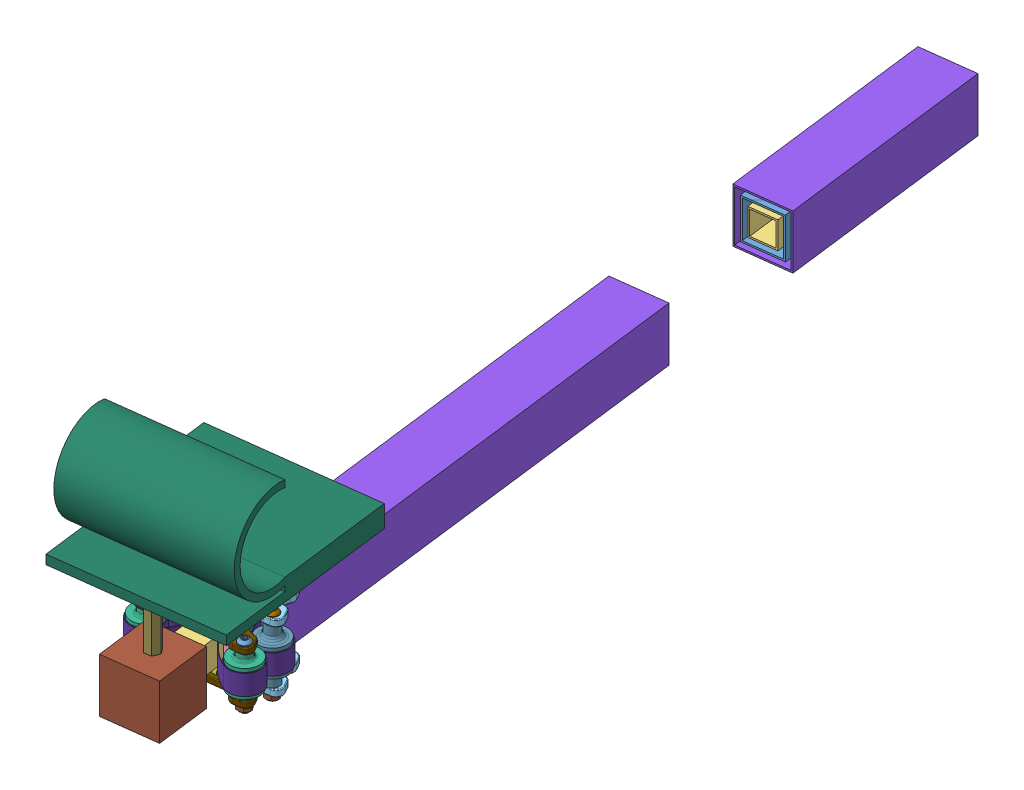
SolidWorks assembly climber prototype2, configuration Default. Lengths in mm.
Overall size (269.94 274.38 951.32).
100 component instances, 33 part files, 13 mates.
Components (placement in the parent):
- 2 x 2 Inch Stage.stp-1: 2 x 2 Inch Stage.stp [Default] at (1113.4745 353.0023 985.2524) size (183.93 74.15 806.3)
  - 1.5_inch_stage.stp-1: 1.5_inch_stage.stp [Default] at (-107.3783 0 -858.4701) size (133.34 47.37 731.79)
    - 1.5x1.5 bar.stp-1: 1.5x1.5 bar.stp [Default] at (575.8182 404.7167 1377.5179) x (-0.992268 0 0.124114) z (-0.124114 0 -0.992268) size (38.1 38.1 711.2)
    - 2x2StageInternalEndBlock.stp-1: 2x2StageInternalEndBlock.stp [Default] at (413.7616 573.8056 681.0462) x (-0.992268 0 0.124114) z (-0.124114 0 -0.992268) size (47.37 47.37 40.64)
    - 94615A115_Brass Flanged Screw-to-Expand Inserts (1).stp-1: 94615A115_Brass Flanged Screw-to-Expand Inserts (1).stp [Default] at (431.7042 573.8056 688.4011) x (0.114575 0.384452 0.916007) z (-0.047716 0.923145 -0.381479) size (7.92 9.53 7.92)
    - 97763A231_18-8 Stainless Steel Button Head Hex Drive Screws.stp-1: 97763A231_18-8 Stainless Steel Button Head Hex Drive Screws.stp [Default] at (398.9269 573.8691 692.501) x (0.124114 0.000773 0.992268) z (-0.992268 0 0.124114) size (9.17 9.17 12.09)
  - 2x2ClimberPlateAssemblyNew.stp-1: 2x2ClimberPlateAssemblyNew.stp [Default] at (310.1471 56.4224 225.65) x (0.992268 0 -0.124114) z (0.124114 0 0.992268) size (102.18 13.04 44.45)
    - 2x2NewClimberPlateConcept.stp-1: 2x2NewClimberPlateConcept.stp [Default] at (71.6924 542.7705 -285.0056) x (-1 0 0) z (0 1 0) size (102.18 44.45 8.76)
    - 98381A545_ALLOY STEEL DOWEL PIN.stp-1: 98381A545_ALLOY STEEL DOWEL PIN.stp [Default] at (46.4194 542.6435 281.8589) x (-1 0 0) z (0 -0.467381 0.884056) size (34.92 6.35 6.35)
    - TTB-0027_.50OD_.25ID_.188WD.stp-1: TTB-0027_.50OD_.25ID_.188WD.stp [Default] at (31.3382 542.6435 281.8589) x (0 0.013886 0.999904) z (-1 0 0) size (12.7 12.7 4.76)
    - TTB-0027_.50OD_.25ID_.188WD.stp-2: TTB-0027_.50OD_.25ID_.188WD.stp [Default] at (61.5007 542.6435 281.8589) x (0 0.005291 0.999986) z (-1 0 0) size (12.7 12.7 4.76)
  - 2x2ClimberPlateAssemblyNew.stp-2: 2x2ClimberPlateAssemblyNew.stp [Default] at (402.0161 1091.1635 214.1589) x (-0.992268 0 0.124114) z (0.124114 0 0.992268) size (102.18 13.04 44.45)
    - 2x2NewClimberPlateConcept.stp-1: 2x2NewClimberPlateConcept.stp [Default] at (71.6924 542.7705 -285.0056) x (-1 0 0) z (0 1 0) size (102.18 44.45 8.76)
    - 98381A545_ALLOY STEEL DOWEL PIN.stp-1: 98381A545_ALLOY STEEL DOWEL PIN.stp [Default] at (46.4194 542.6435 281.8589) x (-1 0 0) z (0 -0.467381 0.884056) size (34.92 6.35 6.35)
    - TTB-0027_.50OD_.25ID_.188WD.stp-1: TTB-0027_.50OD_.25ID_.188WD.stp [Default] at (31.3382 542.6435 281.8589) x (0 0.013886 0.999904) z (-1 0 0) size (12.7 12.7 4.76)
    - TTB-0027_.50OD_.25ID_.188WD.stp-2: TTB-0027_.50OD_.25ID_.188WD.stp [Default] at (61.5007 542.6435 281.8589) x (0 0.005291 0.999986) z (-1 0 0) size (12.7 12.7 4.76)
  - 2x2 Box.stp-1: 2x2 Box.stp [Default] at (320.6921 548.3929 -267.6788) x (-0.992268 0 0.124114) z (0.124114 0 0.992268) size (50.8 50.8 762)
  - 91255A529_NO THREADS_Button Head Hex Drive Screw (1).stp-1: 91255A529_NO THREADS_Button Head Hex Drive Screw (1).stp [Default] at (366.1553 609.0227 504.1716) x (0.396837 0 -0.917889) z (0 1 0) size (11.1 11.1 73.2)
  - 90044A515_Black-Oxide Alloy Steel Socket Head Screw.stp-1: 90044A515_Black-Oxide Alloy Steel Socket Head Screw.stp [Default] at (410.673 605.6699 482.6046) x (0.993633 0 -0.112668) z (0 1 0) size (6.86 6.86 74.15)
  - 90044A515_Black-Oxide Alloy Steel Socket Head Screw.stp-2: 90044A515_Black-Oxide Alloy Steel Socket Head Screw.stp [Default] at (367.8773 605.6699 487.9575) x (0.430705 0 0.902493) z (0 1 0) size (6.86 6.86 74.15)
  - 91255A529_NO THREADS_Button Head Hex Drive Screw (1).stp-2: 91255A529_NO THREADS_Button Head Hex Drive Screw (1).stp [Default] at (351.7432 609.0227 521.973) x (-0.099638 0 0.995024) z (0 1 0) size (11.1 11.1 73.2)
  - 91255A529_NO THREADS_Button Head Hex Drive Screw (1).stp-3: 91255A529_NO THREADS_Button Head Hex Drive Screw (1).stp [Default] at (434.6883 609.0227 511.5981) x (1 0 0) z (0 1 0) size (11.1 11.1 73.2)
  - 91255A529_NO THREADS_Button Head Hex Drive Screw (1).stp-4: 91255A529_NO THREADS_Button Head Hex Drive Screw (1).stp [Default] at (416.3356 609.0227 497.895) x (0.998718 0 -0.050617) z (0 1 0) size (11.1 11.1 73.2)
  - TTB-0027_.50OD_.25ID_.188WD.stp-1: TTB-0027_.50OD_.25ID_.188WD.stp [Default] at (416.3356 557.2004 497.895) x (-0.032207 0 0.999481) z (0 1 0) size (12.7 12.7 4.76)
  - TTB-0027_.50OD_.25ID_.188WD.stp-2: TTB-0027_.50OD_.25ID_.188WD.stp [Default] at (416.3356 590.4617 497.895) x (-0.065423 0 0.997858) z (0 1 0) size (12.7 12.7 4.76)
  - TTB-0027_.50OD_.25ID_.188WD.stp-3: TTB-0027_.50OD_.25ID_.188WD.stp [Default] at (366.1553 557.2004 504.1716) x (-0.065423 0 0.997858) z (0 1 0) size (12.7 12.7 4.76)
  - TTB-0027_.50OD_.25ID_.188WD.stp-4: TTB-0027_.50OD_.25ID_.188WD.stp [Default] at (366.1553 590.4617 504.1716) x (-0.065423 0 0.997858) z (0 1 0) size (12.7 12.7 4.76)
  - 90101A230_18-8 Stainless Steel Thin Nylon-Insert Locknut.stp-1: 90101A230_18-8 Stainless Steel Thin Nylon-Insert Locknut.stp [Default] at (434.6883 541.9159 511.5981) x (0.797272 0 -0.60362) z (-0.60362 0 -0.797272) size (11.11 5.2 12.83)
  - 90101A230_18-8 Stainless Steel Thin Nylon-Insert Locknut.stp-2: 90101A230_18-8 Stainless Steel Thin Nylon-Insert Locknut.stp [Default] at (416.3356 541.9159 497.895) x (0.921386 0 0.388648) z (0.388648 0 -0.921386) size (11.11 5.2 12.83)
  - 90101A230_18-8 Stainless Steel Thin Nylon-Insert Locknut.stp-3: 90101A230_18-8 Stainless Steel Thin Nylon-Insert Locknut.stp [Default] at (351.7432 541.9159 521.973) x (0.797272 0 -0.60362) z (-0.60362 0 -0.797272) size (11.11 5.2 12.83)
  - 90101A230_18-8 Stainless Steel Thin Nylon-Insert Locknut.stp-4: 90101A230_18-8 Stainless Steel Thin Nylon-Insert Locknut.stp [Default] at (366.1553 541.9159 504.1716) x (0.797272 0 -0.60362) z (-0.60362 0 -0.797272) size (11.11 5.2 12.83)
  - QuaterInchTelescopingSpacer.stp-1: QuaterInchTelescopingSpacer.stp [Default] at (391.2422 599.1929 504.1716) x (1 0 0) z (0 -1 0) size (9.27 9.27 6.35)
  - QuaterInchTelescopingSpacer.stp-2: QuaterInchTelescopingSpacer.stp [Default] at (391.2422 554.8191 504.1844) x (1 0 0.000511) z (0 -1 0) size (9.27 9.27 6.35)
  - 1.122InchTelescopingSpacer.stp-1: 1.122InchTelescopingSpacer.stp [Default] at (391.2422 588.0804 504.1716) x (1 0 0) z (0 -1 0) size (8.76 8.76 28.5)
  - QuaterInchTelescopingSpacer.stp-3: QuaterInchTelescopingSpacer.stp [Default] at (440.4399 599.1929 504.8475) x (0.96083 0 0.277139) z (0 -1 0) size (9.27 9.27 6.35)
  - QuaterInchTelescopingSpacer.stp-4: QuaterInchTelescopingSpacer.stp [Default] at (409.5553 554.8191 522.0482) x (-0.270275 0 0.962783) z (0 -1 0) size (9.27 9.27 6.35)
  - 94615A115_Brass Flanged Screw-to-Expand Inserts (1).stp-1: 94615A115_Brass Flanged Screw-to-Expand Inserts (1).stp [Default] at (290.8052 573.8056 -165.8762) x (0.123955 0.050546 0.991) z (0.006274 -0.998722 0.050156) size (7.92 9.53 7.92)
  - 97763A231_18-8 Stainless Steel Button Head Hex Drive Screws.stp-1: 97763A231_18-8 Stainless Steel Button Head Hex Drive Screws.stp [Default] at (323.7085 573.8691 -169.9917) x (-0.124114 0 -0.992268) z (0.992268 0 -0.124114) size (9.17 9.17 12.09)
  - 1.122InchTelescopingSpacer.stp-2: 1.122InchTelescopingSpacer.stp [Default] at (441.4226 588.0804 497.895) x (1 0 0) z (0 -1 0) size (8.76 8.76 28.5)
  - 1InchCFSpringRetentionSpacer_BaseStage.stp-1: 1InchCFSpringRetentionSpacer_BaseStage.stp [Default] at (351.7432 564.2679 521.973) x (1 0 0) z (0 -1 0) size (27.94 27.94 15.88)
  - 1InchCFSpringRetentionSpacer_BaseStage.stp-2: 1InchCFSpringRetentionSpacer_BaseStage.stp [Default] at (434.6883 583.3179 511.5981) x (-0.043542 0 0.999052) z (0 1 0) size (27.94 27.94 15.88)
  - 1InchCFSpringRetentionSpacer_BaseStage.stp-3: 1InchCFSpringRetentionSpacer_BaseStage.stp [Default] at (351.7432 583.3179 521.973) x (1 0 0) z (0 1 0) size (27.94 27.94 15.88)
  - 1InchCFSpringRetentionSpacer_BaseStage.stp-4: 1InchCFSpringRetentionSpacer_BaseStage.stp [Default] at (434.6883 564.2679 511.5981) x (0.999991 0 -0.00417) z (0 -1 0) size (27.94 27.94 15.88)
  - 90101A009_18-8 Stainless Steel Thin Nylon-Insert Locknut (1).stp-1: 90101A009_18-8 Stainless Steel Thin Nylon-Insert Locknut (1).stp [Default] at (368.252 541.9159 487.9106) x (0.797272 0 -0.60362) z (-0.60362 0 -0.797272) size (8.73 4.37 10.08)
  - 9293K56_SpringRoller.stp-1: 9293K56_SpringRoller.stp [Default] at (351.7432 564.2679 521.973) x (0.41705 0 -0.908884) z (0 1 0) size (20.07 20.07 19.05)
  - 9293K56_SpringRoller.stp-2: 9293K56_SpringRoller.stp [Default] at (434.6883 583.3179 511.5981) x (0.41705 0 0.908884) z (0 -1 0) size (20.07 20.07 19.05)
  - 9293K56_Constant-Force Spring.stp-1: 9293K56_Constant-Force Spring.stp [Default] at (434.7326 573.7929 511.5599) x (0 -1 0) z (-0.934501 0 0.355959) size (19.06 41.04 33.21)
  - 9293K56_Constant-Force Spring.stp-2: 9293K56_Constant-Force Spring.stp [Default] at (351.6902 573.7929 521.9484) x (0 1 0) z (0.996341 0 0.085466) size (19.06 41.04 33.21)
  - 90101A009_18-8 Stainless Steel Thin Nylon-Insert Locknut (1).stp-2: 90101A009_18-8 Stainless Steel Thin Nylon-Insert Locknut (1).stp [Default] at (410.673 541.9159 482.6046) x (0.797272 0 -0.60362) z (-0.60362 0 -0.797272) size (8.73 4.37 10.08)
- Stage 2 BOM - 1.5 inch to 1 inch Kit.stp-1: Stage 2 BOM - 1.5 inch to 1 inch Kit.stp [Default] at (1071.3002 772.575 539.439) x (0.992268 0 -0.124114) z (0.124114 0 0.992268) size (125.22 66.32 768.66)
  - 1.5ClimberPlateNewDesign.stp-1: 1.5ClimberPlateNewDesign.stp [Default] at (293.5653 129.5314 1017.7273) x (1 0 0) z (0 1 0) size (98.65 41.27 8)
  - 1.5ClimberPlateNewDesign.stp-2: 1.5ClimberPlateNewDesign.stp [Default] at (331.6653 179.0614 1017.7273) x (-1 0 0) z (0 -1 0) size (98.65 41.27 8)
  - 91255A528_NO THREADS_Button Head Hex Drive Screw.stp-1: 91255A528_NO THREADS_Button Head Hex Drive Screw.stp [Default] at (354.2078 182.4142 1039.3173) x (0.997583 0 0.069478) z (0 1 0) size (11.1 11.1 60.5)
  - 91255A528_NO THREADS_Button Head Hex Drive Screw.stp-2: 91255A528_NO THREADS_Button Head Hex Drive Screw.stp [Default] at (331.551 182.4142 1025.9823) x (1 0 0.000115) z (0 1 0) size (11.1 11.1 60.5)
  - 91255A528_NO THREADS_Button Head Hex Drive Screw.stp-3: 91255A528_NO THREADS_Button Head Hex Drive Screw.stp [Default] at (293.6796 182.4142 1025.9823) x (0.942114 0 0.335293) z (0 1 0) size (11.1 11.1 60.5)
  - 91255A528_NO THREADS_Button Head Hex Drive Screw.stp-4: 91255A528_NO THREADS_Button Head Hex Drive Screw.stp [Default] at (271.0228 182.4142 1039.3173) x (1 0 0) z (0 1 0) size (11.1 11.1 60.5)
  - 98381A542_ALLOY STEEL DOWEL PIN.stp-1: 98381A542_ALLOY STEEL DOWEL PIN.stp [Default] at (312.5899 173.2194 1025.9545) x (1 0 0) z (0 -0.047568 0.998868) size (25.4 6.35 6.35)
  - 98381A542_ALLOY STEEL DOWEL PIN.stp-2: 98381A542_ALLOY STEEL DOWEL PIN.stp [Default] at (312.5899 135.3734 1025.9545) x (1 0 0) z (0 -0.129807 0.991539) size (25.4 6.35 6.35)
  - TTB-0027_.50OD_.25ID_.188WD.stp-1: TTB-0027_.50OD_.25ID_.188WD.stp [Default] at (322.7054 135.3734 1025.9545) x (0 -0.059569 0.998224) z (-1 0 0) size (12.7 12.7 4.76)
  - TTB-0027_.50OD_.25ID_.188WD.stp-2: TTB-0027_.50OD_.25ID_.188WD.stp [Default] at (302.4743 135.3734 1025.9545) x (0 0.249065 0.968487) z (-1 0 0) size (12.7 12.7 4.76)
  - TTB-0027_.50OD_.25ID_.188WD.stp-3: TTB-0027_.50OD_.25ID_.188WD.stp [Default] at (293.6796 166.19 1025.9823) x (-0.99026 0 0.139228) z (0 1 0) size (12.7 12.7 4.76)
  - TTB-0027_.50OD_.25ID_.188WD.stp-4: TTB-0027_.50OD_.25ID_.188WD.stp [Default] at (293.6796 142.2505 1025.9823) x (1 0 0) z (0 1 0) size (12.7 12.7 4.76)
  - TTB-0027_.50OD_.25ID_.188WD.stp-5: TTB-0027_.50OD_.25ID_.188WD.stp [Default] at (331.551 166.19 1025.9823) x (-0.070413 0 0.997518) z (0 1 0) size (12.7 12.7 4.76)
  - TTB-0027_.50OD_.25ID_.188WD.stp-6: TTB-0027_.50OD_.25ID_.188WD.stp [Default] at (302.4743 173.2194 1025.9545) x (0 -0.065423 0.997858) z (-1 0 0) size (12.7 12.7 4.76)
  - TTB-0027_.50OD_.25ID_.188WD.stp-7: TTB-0027_.50OD_.25ID_.188WD.stp [Default] at (322.7054 173.2194 1025.9545) x (0 0.136778 0.990602) z (-1 0 0) size (12.7 12.7 4.76)
  - TTB-0027_.50OD_.25ID_.188WD.stp-8: TTB-0027_.50OD_.25ID_.188WD.stp [Default] at (331.551 142.2505 1025.9823) x (1 0 0) z (0 1 0) size (12.7 12.7 4.76)
  - 1x1.stp-1: 1x1.stp [Default] at (299.8518 166.9329 770.3868) x (0 -1 0) z (-1 0 0) size (25.4 711.2 25.4)
  - 90101A230_18-8 Stainless Steel Thin Nylon-Insert Locknut.stp-1: 90101A230_18-8 Stainless Steel Thin Nylon-Insert Locknut.stp [Default] at (293.6796 129.5314 1025.9823) x (0.866025 0 -0.5) z (-0.5 0 -0.866025) size (11.11 5.2 12.83)
  - 90101A230_18-8 Stainless Steel Thin Nylon-Insert Locknut.stp-2: 90101A230_18-8 Stainless Steel Thin Nylon-Insert Locknut.stp [Default] at (354.2078 129.5314 1039.3173) x (-0.866025 0 -0.5) z (-0.5 0 0.866025) size (11.11 5.2 12.83)
  - 90101A230_18-8 Stainless Steel Thin Nylon-Insert Locknut.stp-3: 90101A230_18-8 Stainless Steel Thin Nylon-Insert Locknut.stp [Default] at (331.551 129.5314 1025.9823) x (0.866025 0 0.5) z (0.5 0 -0.866025) size (11.11 5.2 12.83)
  - 90101A230_18-8 Stainless Steel Thin Nylon-Insert Locknut.stp-4: 90101A230_18-8 Stainless Steel Thin Nylon-Insert Locknut.stp [Default] at (271.0228 129.5314 1039.3173) x (0.866025 0 0.5) z (0.5 0 -0.866025) size (11.11 5.2 12.83)
  - .607TelescopingSpacer.stp-1: .607TelescopingSpacer.stp [Default] at (354.9872 144.6317 1017.0327) x (0.934202 0 -0.356745) z (0 1 0) size (9.02 9.02 19.18)
  - .607TelescopingSpacer.stp-2: .607TelescopingSpacer.stp [Default] at (318.7665 144.6317 1026.006) x (1 0 0.000943) z (0 1 0) size (9.02 9.02 19.18)
  - .188TelescopingSpacer.stp-1: .188TelescopingSpacer.stp [Default] at (356.6379 173.3464 1025.9823) x (1 0 0) z (0 -1 0) size (8.81 8.81 4.78)
  - .188TelescopingSpacer.stp-2: .188TelescopingSpacer.stp [Default] at (318.7665 173.3464 1025.9823) x (1 0 0) z (0 -1 0) size (8.81 8.81 4.78)
  - .188TelescopingSpacer.stp-3: .188TelescopingSpacer.stp [Default] at (282.8338 139.8692 1048.6036) x (-0.432328 0 0.901716) z (0 -1 0) size (8.81 8.81 4.78)
  - .188TelescopingSpacer.stp-4: .188TelescopingSpacer.stp [Default] at (326.9008 139.8692 1001.3302) x (-0.18536 0 -0.982671) z (0 -1 0) size (8.81 8.81 4.78)
  - 9293K56_Constant-Force Spring.stp-1: 9293K56_Constant-Force Spring.stp [Default] at (354.2389 154.2964 1039.2678) x (0 -1 0) z (-0.788944 0 0.614465) size (19.06 41.04 33.21)
  - 1InchCFSpringRetentionSpacer.stp-1: 1InchCFSpringRetentionSpacer.stp [Default] at (271.0228 144.7714 1039.3173) x (0.41705 0 0.908884) z (0 -1 0) size (27.94 27.94 9.53)
  - 1InchCFSpringRetentionSpacer.stp-2: 1InchCFSpringRetentionSpacer.stp [Default] at (354.2078 144.7714 1039.3173) x (0.383782 0 0.923424) z (0 -1 0) size (27.94 27.94 9.53)
  - 1InchCFSpringRetentionSpacer.stp-3: 1InchCFSpringRetentionSpacer.stp [Default] at (354.2078 163.8214 1039.3173) x (0.830028 0 -0.557722) z (0 1 0) size (27.94 27.94 9.53)
  - 1InchCFSpringRetentionSpacer.stp-4: 1InchCFSpringRetentionSpacer.stp [Default] at (271.0228 163.8214 1039.3173) x (0.383782 0 -0.923424) z (0 1 0) size (27.94 27.94 9.53)
  - 9293K56_Constant-Force Spring.stp-2: 9293K56_Constant-Force Spring.stp [Default] at (270.9861 154.2964 1039.2718) x (0 1 0) z (0.855643 0 0.517566) size (19.06 41.04 33.21)
  - 9293K56_SpringRoller.stp-1: 9293K56_SpringRoller.stp [Default] at (271.0228 163.8214 1039.3173) x (0.416799 0 0.908999) z (0 -1 0) size (20.07 20.07 19.05)
  - 1x1StageInternalEndBlock.stp-1: 1x1StageInternalEndBlock.stp [Default] at (312.6153 154.2964 363.9868) x (-1 0 0) z (0 0 -1) size (34.67 34.67 40)
  - 90101A009_18-8 Stainless Steel Thin Nylon-Insert Locknut (1).stp-1: 90101A009_18-8 Stainless Steel Thin Nylon-Insert Locknut (1).stp [Default] at (327.8299 129.5314 1011.3773) x (0.866025 0 0.5) z (0.5 0 -0.866025) size (8.73 4.37 10.08)
  - 90101A009_18-8 Stainless Steel Thin Nylon-Insert Locknut (1).stp-2: 90101A009_18-8 Stainless Steel Thin Nylon-Insert Locknut (1).stp [Default] at (297.4007 129.5314 1011.3773) x (-0.866025 0 -0.5) z (-0.5 0 0.866025) size (8.73 4.37 10.08)
  - 90044A513_Black-Oxide Alloy Steel Socket Head Screw.stp-1: 90044A513_Black-Oxide Alloy Steel Socket Head Screw.stp [Default] at (297.4007 179.0614 1011.3773) x (0.353324 0 0.935501) z (0 1 0) size (10.11 10 66.32)
  - 90044A513_Black-Oxide Alloy Steel Socket Head Screw.stp-2: 90044A513_Black-Oxide Alloy Steel Socket Head Screw.stp [Default] at (327.8299 179.0614 1011.3773) x (1 0 0) z (0 1 0) size (10.11 10 66.32)
  - 94615A212_Brass Flanged Screw-to-Expand Inserts (1).stp-1: 94615A212_Brass Flanged Screw-to-Expand Inserts (1).stp [Default] at (301.9473 154.2964 373.5118) x (0 -0.59679 -0.802398) z (0 0.802398 -0.59679) size (7.14 7.14 7.14)
  - 94615A212_Brass Flanged Screw-to-Expand Inserts (1).stp-2: 94615A212_Brass Flanged Screw-to-Expand Inserts (1).stp [Default] at (323.2833 154.2964 373.5118) x (0 0.670342 -0.742052) z (0 -0.742052 -0.670342) size (7.14 7.14 7.14)
  - 97763A504_18-8 Stainless Steel Button Head Hex Drive Screws.stp-1: 97763A504_18-8 Stainless Steel Button Head Hex Drive Screws.stp [Default] at (302.0806 154.2964 373.5118) x (0 0 1) z (-1 0 0) size (7.92 7.92 10.15)
  - 97763A504_18-8 Stainless Steel Button Head Hex Drive Screws.stp-2: 97763A504_18-8 Stainless Steel Button Head Hex Drive Screws.stp [Default] at (323.0229 154.2964 373.5118) x (0 0 -1) z (1 0 0) size (7.92 7.92 10.15)
  - 1.5x1.5 bar.stp-1: 1.5x1.5 bar.stp [Default] at (386.9135 -14.856 1017.7273) x (-1 0 0) z (0 0 -1) size (38.1 38.1 711.2)
  - 9293K56_SpringRoller.stp-2: 9293K56_SpringRoller.stp [Default] at (354.2078 163.8214 1039.3173) x (0.416799 0 0.908999) z (0 -1 0) size (20.07 20.07 19.05)
- block for climber-1: block for climber [Default] at (1512.9894 926.808 1552.3982) x (0 1 0) z (0.992268 0 -0.124114) size (50.8 50.8 50.8)
- Hex shaft for climber-1: Hex shaft for climber [Default] at (1516.1419 914.108 1577.6018) x (0 1 0) z (0.992268 0 -0.124114) size (115.41 12 13.86)
- half in hex bearing for clibmer-2: half in hex bearing for clibmer [Default] at (1516.1419 1028.4613 1577.6018) x (0.992268 0 -0.124114) z (0 -1 0) size (31.12 31.12 7.93)
- wood piece for pivot in climber-1: wood piece for pivot in climber [Default] at (1516.1419 1022.058 1577.6018) x (0 1 0) z (0.992268 0 -0.124114) size (6.35 38.1 101.6)
- claw for clibmer-2: claw for clibmer [Default] at (1616.6946 1085.4418 1562.8992) x (-0.07906 -0.770864 -0.632074) z (-0.992268 0 0.124114) size (163.93 145.18 152.4)
Mates (geometry in assembly coordinates):
- Coincident4: coincident anti-aligned: plane of block for climber-1 through (1512.9894 914.108 1552.3982) normal (0 1 0); plane of Hex shaft for climber-1 through (1516.1419 914.108 1577.6018) normal (0 -1 0)
- Coincident5: coincident anti-aligned: plane of block for climber-1 through (1509.2673 914.108 1578.4617) normal (0.797272 0 -0.60362); plane of Hex shaft for climber-1 through (1509.2673 1028.408 1578.4617) normal (-0.797272 0 0.60362)
- Coincident6: coincident anti-aligned: plane of block for climber-1 through (1520.3239 914.108 1583.1255) normal (-0.921386 0 -0.388648); plane of Hex shaft for climber-1 through (1520.3239 1028.408 1583.1255) normal (0.921386 0 0.388648)
- Concentric1: concentric anti-aligned: cylinder of half in hex bearing for clibmer-2 through (1516.1419 1020.534 1577.6018) axis (0 1 0) radius 14.2875; cylinder of wood piece for pivot in climber-1 through (1516.1419 1028.408 1577.6018) axis (0 -1 0) radius 15.494
- Coincident7: coincident anti-aligned: plane of half in hex bearing for clibmer-2 through (1530.0039 1022.058 1575.8679) normal (0 1 0); plane of wood piece for pivot in climber-1 through (1516.1419 1022.058 1577.6018) normal (0 -1 0)
- Concentric2: concentric anti-aligned: circle of Hex shaft for climber-1; circle of half in hex bearing for clibmer-2
- Coincident8: coincident anti-aligned: plane of wood piece for pivot in climber-1 through (1516.1419 1028.408 1577.6018) normal (0 1 0); plane of claw for clibmer-2 through (1463.3703 1028.408 1565.0041) normal (0 -1 0)
- Coincident10: coincident aligned: plane of wood piece for pivot in climber-1 through (1463.3703 1028.408 1565.0041) normal (-0.992268 0 0.124114); plane of claw for clibmer-2 through (1465.4729 1085.4418 1581.8141) normal (-0.992268 0 0.124114)
- Coincident14: coincident anti-aligned: plane of Stage 2 BOM - 1.5 inch to 1 inch Kit.stp-1/1x1.stp-1 through (1502.2791 939.508 1569.0966) normal (0.124114 0 0.992268); plane of block for climber-1 through (1514.8809 926.808 1567.5204) normal (-0.124114 0 -0.992268)
- Parallel3: parallel aligned: plane of Hex shaft for climber-1 through (1523.0165 1028.408 1576.7419) normal (0.797272 0 -0.60362); plane of half in hex bearing for clibmer-2 through (1508.8662 1020.534 1578.5119) normal (0.797272 0 -0.60362)
- Coincident16: coincident anti-aligned: plane of Hex shaft for climber-1 through (1516.1419 1028.408 1577.6018) normal (0 1 0); plane of claw for clibmer-2 through (1463.3703 1028.408 1565.0041) normal (0 -1 0)
- Coincident17: coincident anti-aligned: plane of Stage 2 BOM - 1.5 inch to 1 inch Kit.stp-1/1x1.stp-1 through (1527.4827 939.508 1565.9441) normal (0.992268 0 -0.124114); plane of block for climber-1 through (1527.4827 914.108 1565.9441) normal (-0.992268 0 0.124114)
- Coincident18: coincident anti-aligned: plane of Stage 2 BOM - 1.5 inch to 1 inch Kit.stp-1/1x1.stp-1 through (1502.2791 914.108 1569.0966) normal (0 -1 0); plane of block for climber-1 through (1527.4827 914.108 1565.9441) normal (0 1 0)
